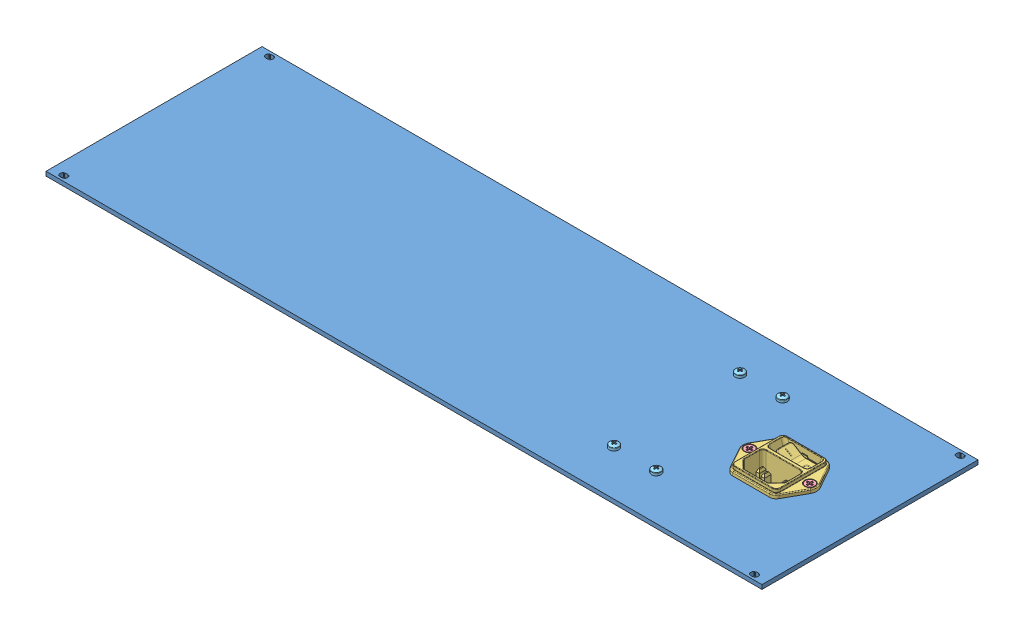
SolidWorks assembly MLA-0387-M2, configuration Default. Lengths in mm.
Overall size (426.52 36.95 128.7).
21 component instances, 7 part files, 36 mates.
Components (placement in the parent):
- MLA-0387-M3-1: MLA-0387-M3 [Default] at (14.077 -174.6299 585.4715) size (426.52 2.5 128.7)
- ECL15US12-S-1: ECL15US12-S [Default] at (340.987 202.9701 302.5215) x (0 0 -1) z (1 0 0) size (84 26.49 34.5)
- DC11_0001_001-1: DC11_0001_001 [Default] at (389.437 205.4701 308.5715) x (1 0 0) z (0 1 0) size (44 34 36.95)
- SCREW_ISO 7046-1: SCREW_ISO 7046 [VIJAK M 3x 10] at (371.437 207.6701 302.5215) x (0 -1 0) z (0 0 1) size (10 5.6 5.6)
- SCREW_ISO 7046-2: SCREW_ISO 7046 [VIJAK M 3x 10] at (407.437 207.6701 302.5215) x (0 -1 0) z (0 0 1) size (10 5.6 5.6)
- M3 X 10mm Screw-1: M3 X 10mm Screw [Default] at (328.287 207.8701 340.0215) x (0 -1 0) z (0 0 1) size (12.61 5.6 5.6)
- M3 X 10mm Screw-2: M3 X 10mm Screw [Default] at (353.687 207.8701 340.2611) x (0 -1 0) z (0 0 1) size (12.61 5.6 5.6)
- M3 X 10mm Screw-3: M3 X 10mm Screw [Default] at (353.687 207.8701 265.0215) x (0 -1 0) z (0 0 1) size (12.61 5.6 5.6)
- M3 X 10mm Screw-4: M3 X 10mm Screw [Default] at (328.287 207.8701 265.0215) x (0 -1 0) z (0 0 1) size (12.61 5.6 5.6)
- M3 screw size FLAT WASHER-1: M3 screw size FLAT WASHER [Default] at (407.437 202.9701 302.5215) x (0.944963 0 -0.327176) z (0 -1 0) size (7 7 0.6)
- M3 screw size FLAT WASHER-2: M3 screw size FLAT WASHER [Default] at (371.437 202.3701 302.5215) x (1 0 0) z (0 1 0) size (7 7 0.6)
- M3 x 0.5mm Thread HEX NUT-1: M3 x 0.5mm Thread HEX NUT [Default] at (407.4348 201.1701 302.5562) x (1 0 0) z (0 1 0) size (5.5 6.35 2.6)
- M3 x 0.5mm Thread HEX NUT-2: M3 x 0.5mm Thread HEX NUT [Default] at (371.4463 201.1701 302.55) x (1 0 0) z (0 1 0) size (5.5 6.35 2.6)
- M3 screw size FLAT WASHER-3: M3 screw size FLAT WASHER [Default] at (353.687 199.8701 340.2611) x (1 0 0) z (0 1 0) size (7 7 0.6)
- M3 screw size FLAT WASHER-4: M3 screw size FLAT WASHER [Default] at (328.287 199.8701 340.0215) x (1 0 0) z (0 1 0) size (7 7 0.6)
- M3 screw size FLAT WASHER-5: M3 screw size FLAT WASHER [Default] at (328.287 200.4701 265.0215) x (1 0 0) z (0 -1 0) size (7 7 0.6)
- M3 screw size FLAT WASHER-6: M3 screw size FLAT WASHER [Default] at (353.687 200.4701 265.0215) x (1 0 0) z (0 -1 0) size (7 7 0.6)
- M3 x 0.5mm Thread HEX NUT-3: M3 x 0.5mm Thread HEX NUT [Default] at (328.3059 198.6701 265.0157) x (1 0 0) z (0 -1 0) size (5.5 6.35 2.6)
- M3 x 0.5mm Thread HEX NUT-4: M3 x 0.5mm Thread HEX NUT [Default] at (353.679 198.6701 264.9262) x (1 0 0) z (0 -1 0) size (5.5 6.35 2.6)
- M3 x 0.5mm Thread HEX NUT-5: M3 x 0.5mm Thread HEX NUT [Default] at (353.654 198.6701 340.285) x (1 0 0) z (0 1 0) size (5.5 6.35 2.6)
- M3 x 0.5mm Thread HEX NUT-6: M3 x 0.5mm Thread HEX NUT [Default] at (328.2745 198.6701 340.0301) x (1 0 0) z (0 1 0) size (5.5 6.35 2.6)
Mates (geometry in assembly coordinates):
- Coincident1: coincident anti-aligned: plane of MLA-0387-M3-1 through (22.1573 202.9701 282.3956) normal (0 -1 0); plane of ECL15US12-S-1 through (358.237 202.9701 335.5215) normal (0 1 0)
- Distance1: distance = 22.35 mm aligned: line of ECL15US12-S-1 through (324.7368 202.9701 344.5215) axis (1 0 0); plane of MLA-0387-M3-1 through (443.237 202.9701 366.8715) normal (0 0 1)
- Coincident8: coincident anti-aligned: plane of MLA-0387-M3-1 through (22.1573 205.4701 282.3956) normal (0 1 0); plane of DC11_0001_001-1 through (378.437 205.4701 289.5215) normal (0 -1 0)
- Concentric2: concentric anti-aligned: cylinder of MLA-0387-M3-1 through (371.437 212.9701 302.5215) axis (0 -1 0) radius 1.8; cylinder of DC11_0001_001-1 through (371.437 207.6701 302.5215) axis (0 1 0) radius 1.6
- Concentric3: concentric anti-aligned: cylinder of MLA-0387-M3-1 through (407.437 212.9701 302.5215) axis (0 -1 0) radius 1.8; cylinder of DC11_0001_001-1 through (407.437 207.6701 302.5215) axis (0 1 0) radius 1.6
- Distance4: distance = 85 mm: line of MLA-0387-M3-1 through (443.237 202.9701 366.8715) axis (0 0 -1); line of ECL15US12-S-1 through (358.237 202.9701 343.5217) axis (0 0 -1)
- Concentric4: concentric aligned: cone of DC11_0001_001-1 through (371.437 207.4701 302.5215) axis (0 -1 0); cone of SCREW_ISO 7046-1 through (371.437 206.1701 302.5215) axis (0 -1 0)
- Coincident9: coincident aligned: plane of DC11_0001_001-1 through (378.437 207.6701 289.5215) normal (0 1 0); plane of SCREW_ISO 7046-1 through (371.437 207.6701 302.5215) normal (0 1 0)
- Concentric5: concentric aligned: cone of DC11_0001_001-1 through (407.437 207.4701 302.5215) axis (0 -1 0); cone of SCREW_ISO 7046-2 through (407.437 206.1701 302.5215) axis (0 -1 0)
- Coincident10: coincident aligned: plane of DC11_0001_001-1 through (378.437 207.6701 289.5215) normal (0 1 0); plane of SCREW_ISO 7046-2 through (407.437 207.6701 302.5215) normal (0 1 0)
- Coincident11: coincident anti-aligned: plane of MLA-0387-M3-1 through (22.1573 205.4701 282.3956) normal (0 1 0); plane of M3 X 10mm Screw-1 through (328.287 205.4701 338.5215) normal (0 -1 0)
- Concentric6: concentric aligned: cylinder of MLA-0387-M3-1 through (328.287 212.9701 340.0215) axis (0 -1 0) radius 1.8; cylinder of M3 X 10mm Screw-1 through (328.287 195.4701 340.0215) axis (0 -1 0) radius 2.8
- Coincident12: coincident anti-aligned: plane of MLA-0387-M3-1 through (22.1573 205.4701 282.3956) normal (0 1 0); plane of M3 X 10mm Screw-2 through (353.687 205.4701 338.7611) normal (0 -1 0)
- Concentric7: concentric aligned: cylinder of MLA-0387-M3-1 through (353.687 212.9701 340.2611) axis (0 -1 0) radius 1.8; cylinder of M3 X 10mm Screw-2 through (353.687 195.4701 340.2611) axis (0 -1 0) radius 2.8
- Coincident13: coincident anti-aligned: plane of MLA-0387-M3-1 through (22.1573 205.4701 282.3956) normal (0 1 0); plane of M3 X 10mm Screw-3 through (353.687 205.4701 263.5215) normal (0 -1 0)
- Concentric8: concentric aligned: cylinder of MLA-0387-M3-1 through (353.687 212.9701 265.0215) axis (0 -1 0) radius 1.8; cylinder of M3 X 10mm Screw-3 through (353.687 195.4701 265.0215) axis (0 -1 0) radius 2.8
- Coincident14: coincident anti-aligned: plane of MLA-0387-M3-1 through (22.1573 205.4701 282.3956) normal (0 1 0); plane of M3 X 10mm Screw-4 through (328.287 205.4701 263.5215) normal (0 -1 0)
- Concentric9: concentric aligned: cylinder of MLA-0387-M3-1 through (328.287 212.9701 265.0215) axis (0 -1 0) radius 1.8; cylinder of M3 X 10mm Screw-4 through (328.287 195.4701 265.0215) axis (0 -1 0) radius 2.8
- Coincident15: coincident anti-aligned: plane of MLA-0387-M3-1 through (22.1573 202.9701 282.3956) normal (0 -1 0); plane of M3 screw size FLAT WASHER-1 through (407.437 202.9701 302.5215) normal (0 1 0)
- Concentric10: concentric anti-aligned: cylinder of M3 screw size FLAT WASHER-1 through (407.437 202.3701 302.5215) axis (0 1 0) radius 1.6; cylinder of SCREW_ISO 7046-2 through (407.437 197.6701 302.5215) axis (0 -1 0) radius 2.8
- Coincident16: coincident anti-aligned: plane of MLA-0387-M3-1 through (22.1573 202.9701 282.3956) normal (0 -1 0); plane of M3 screw size FLAT WASHER-2 through (371.437 202.9701 302.5215) normal (0 1 0)
- Concentric11: concentric aligned: cylinder of MLA-0387-M3-1 through (371.437 212.9701 302.5215) axis (0 -1 0) radius 1.8; cylinder of M3 screw size FLAT WASHER-2 through (371.437 202.9701 302.5215) axis (0 -1 0) radius 1.6
- Coincident17: coincident anti-aligned: plane of M3 screw size FLAT WASHER-1 through (407.437 202.3701 302.5215) normal (0 -1 0); plane of M3 x 0.5mm Thread HEX NUT-1 through (404.6848 202.3701 300.9685) normal (0 1 0)
- Coincident18: coincident anti-aligned: plane of M3 screw size FLAT WASHER-2 through (371.437 202.3701 302.5215) normal (0 -1 0); plane of M3 x 0.5mm Thread HEX NUT-2 through (368.6963 202.3701 300.9623) normal (0 1 0)
- Coincident19: coincident anti-aligned: plane of ECL15US12-S-1 through (358.237 200.4701 335.0215) normal (0 -1 0); plane of M3 screw size FLAT WASHER-3 through (353.687 200.4701 340.2611) normal (0 1 0)
- Concentric13: concentric aligned: cylinder of M3 X 10mm Screw-2 through (353.687 195.4701 340.2611) axis (0 -1 0) radius 2.8; cylinder of M3 screw size FLAT WASHER-3 through (353.687 200.4701 340.2611) axis (0 -1 0) radius 3.5
- Coincident20: coincident anti-aligned: plane of ECL15US12-S-1 through (358.237 200.4701 335.0215) normal (0 -1 0); plane of M3 screw size FLAT WASHER-4 through (328.287 200.4701 340.0215) normal (0 1 0)
- Concentric14: concentric aligned: cylinder of M3 X 10mm Screw-1 through (328.287 195.4701 340.0215) axis (0 -1 0) radius 2.8; cylinder of M3 screw size FLAT WASHER-4 through (328.287 200.4701 340.0215) axis (0 -1 0) radius 3.5
- Coincident21: coincident anti-aligned: plane of ECL15US12-S-1 through (358.237 200.4701 270.0215) normal (0 -1 0); plane of M3 screw size FLAT WASHER-5 through (328.287 200.4701 265.0215) normal (0 1 0)
- Concentric15: concentric aligned: cylinder of M3 X 10mm Screw-4 through (328.287 195.4701 265.0215) axis (0 -1 0) radius 2.8; circle of M3 screw size FLAT WASHER-5
- Coincident22: coincident anti-aligned: plane of ECL15US12-S-1 through (358.237 200.4701 270.0215) normal (0 -1 0); plane of M3 screw size FLAT WASHER-6 through (353.687 200.4701 265.0215) normal (0 1 0)
- Concentric16: concentric anti-aligned: circle of M3 X 10mm Screw-3; cylinder of M3 screw size FLAT WASHER-6 through (353.687 199.8701 265.0215) axis (0 1 0) radius 3.5
- Coincident24: coincident anti-aligned: plane of M3 screw size FLAT WASHER-5 through (328.287 199.8701 265.0215) normal (0 -1 0); plane of M3 x 0.5mm Thread HEX NUT-3 through (325.5559 199.8701 266.6034) normal (0 1 0)
- Coincident25: coincident anti-aligned: plane of M3 screw size FLAT WASHER-6 through (353.687 199.8701 265.0215) normal (0 -1 0); plane of M3 x 0.5mm Thread HEX NUT-4 through (350.929 199.8701 266.5139) normal (0 1 0)
- Coincident26: coincident anti-aligned: plane of M3 screw size FLAT WASHER-3 through (353.687 199.8701 340.2611) normal (0 -1 0); plane of M3 x 0.5mm Thread HEX NUT-5 through (350.904 199.8701 338.6973) normal (0 1 0)
- Coincident27: coincident anti-aligned: plane of M3 screw size FLAT WASHER-4 through (328.287 199.8701 340.0215) normal (0 -1 0); plane of M3 x 0.5mm Thread HEX NUT-6 through (325.5245 199.8701 338.4424) normal (0 1 0)
